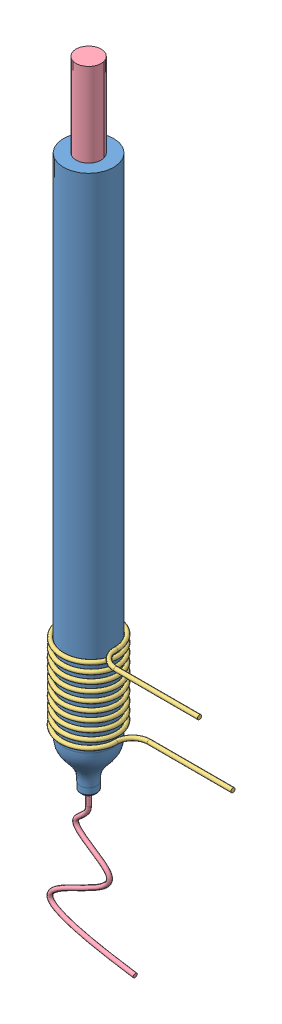
SolidWorks assembly InductionHeatingExtruder, configuration Default. Lengths in mm.
Overall size (20.12 92.58 7.36).
4 component instances, 4 part files, 7 mates.
Components (placement in the parent):
- GlassNozzle_thinwall-1: GlassNozzle_thinwall [Default] at origin size (6 66 6)
- InductionRing_wide-1: InductionRing_wide [Default] at origin size (3 1 3)
- PrimaryCoil-1: PrimaryCoil [Default] at (0 11.2317 0) x (1 0 0) z (0 -1 0) size (18.93 7.36 10.2)
- Plastic^InductionHeatingExtruder-1: Plastic^InductionHeatingExtruder [Default] at origin size (10.48 92.58 3) (virtual)
Mates (geometry in assembly coordinates):
- Coincident1: coincident aligned: plane of GlassNozzle_thinwall-1 through (0 0 0) normal (0 0 1); plane of assembly through (0 0 0) normal (0 0 1)
- Coincident2: coincident aligned: plane of GlassNozzle_thinwall-1 through (0 0 0) normal (0 1 0); plane of assembly through (0 0 0) normal (0 1 0)
- Coincident3: coincident aligned: plane of GlassNozzle_thinwall-1 through (0 0 0) normal (1 0 0); plane of assembly through (0 0 0) normal (1 0 0)
- Coincident4: coincident anti-aligned: plane of GlassNozzle_thinwall-1 through (0 0 0) normal (0 1 0); plane of InductionRing_wide-1 through (1.25 0 0) normal (0 -1 0)
- Concentric1: concentric anti-aligned: cylinder of GlassNozzle_thinwall-1 through (0 0 0) axis (0 1 0) radius 3; cylinder of InductionRing_wide-1 through (0 0 0) axis (0 -1 0) radius 1.5
- Concentric2: concentric anti-aligned: cylinder of GlassNozzle_thinwall-1 through (0 0 0) axis (0 1 0) radius 3; line of PrimaryCoil-1 through (0 12.3528 0) axis (0 -1 0)
- Coincident6: coincident aligned: plane of PrimaryCoil-1 through (0 11.2317 0) normal (0 0 1); plane of ?
